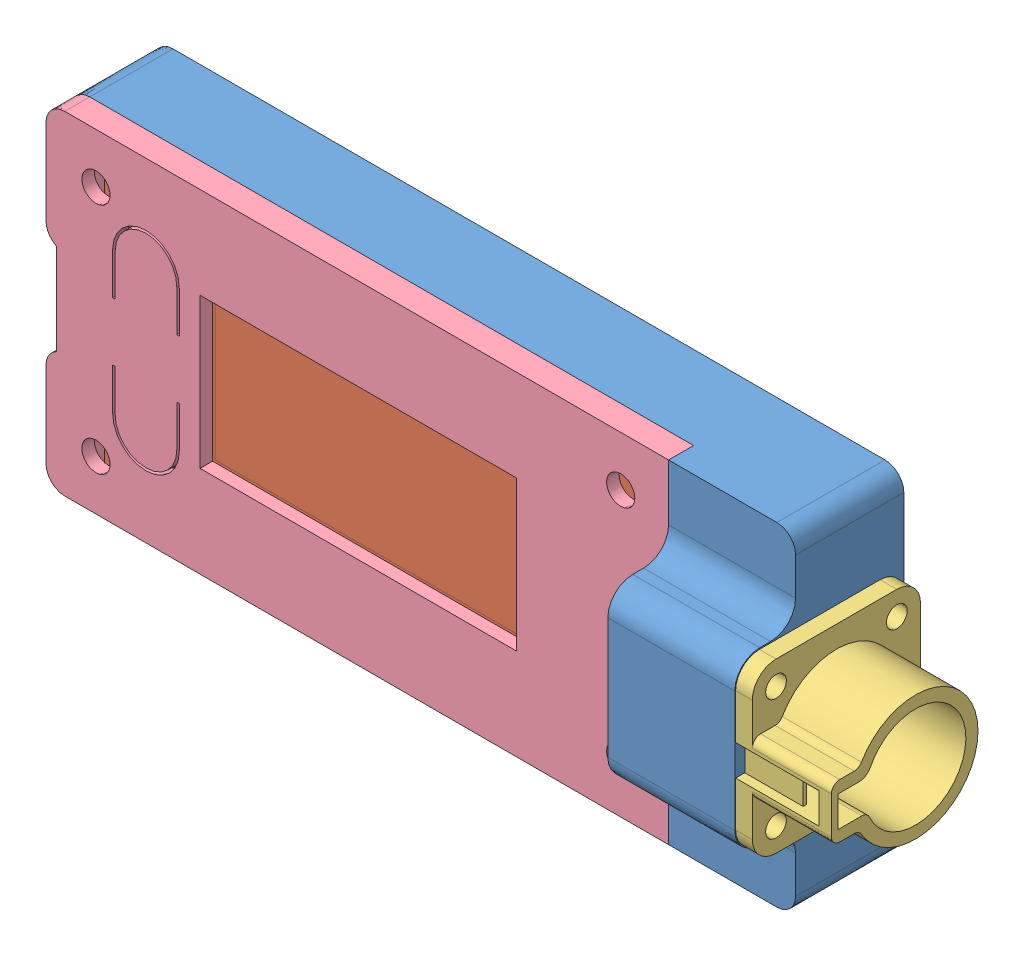
SolidWorks assembly ass-long, configuration Default. Lengths in mm.
Overall size (101.5 40 32.8).
4 component instances, 4 part files, 9 mates.
Components (placement in the parent):
- etna-1: etna [Default] at (-37.6304 -7.9619 -92.9396) size (90 40 20.3)
- pcb01-main-2: pcb01-main [Default] at (-0.1304 12.0381 -83.9396) x (-1 0 0) z (0 0 -1) size (71 35 12)
- RPC1-12RB-6P-1: RPC1-12RB-6P [Default] at (54.3696 12.0381 -82.8396) x (0 -1 0) z (-1 0 0) size (20.2 20.2 22.2)
- etna-top-1: etna-top [Default] at (-37.6304 -7.9619 -82.9396) size (74.75 40 3.7)
Mates (geometry in assembly coordinates):
- Coincident1: coincident anti-aligned: plane of etna-1 through (-37.6304 -7.9619 -83.9396) normal (0 0 1); plane of pcb01-main-2 through (34.8696 -5.4619 -83.9396) normal (0 0 -1)
- Concentric1: concentric aligned: circle of etna-1; circle of pcb01-main-2
- Concentric2: concentric aligned: circle of etna-1; circle of pcb01-main-2
- Width1: width anti-aligned: plane of RPC1-12RB-6P-1 through (54.3696 22.1381 -90.0896) normal (0 1 0); plane of RPC1-12RB-6P-1 through (54.3696 1.9381 -75.5896) normal (0 -1 0); plane of etna-1 through (-37.6304 -7.9619 -82.9396) normal (0 -1 0); plane of etna-1 through (-37.6304 32.0381 -82.9396) normal (0 1 0)
- Coincident5: coincident aligned: plane of etna-1 through (-37.6304 -7.9619 -92.9396) normal (0 0 -1); plane of RPC1-12RB-6P-1 through (54.3696 4.7881 -92.9396) normal (0 0 -1)
- Coincident7: coincident anti-aligned: plane of etna-1 through (52.3696 -7.9619 -82.9396) normal (1 0 0); plane of RPC1-12RB-6P-1 through (52.3696 12.0381 -82.8396) normal (-1 0 0)
- Coincident8: coincident aligned: plane of etna-1 through (-37.6304 -7.9619 -82.9396) normal (0 -1 0); plane of etna-top-1 through (-37.6304 -7.9619 -79.9396) normal (0 -1 0)
- Coincident9: coincident anti-aligned: plane of etna-1 through (-37.6304 -7.9619 -82.9396) normal (0 0 1); plane of etna-top-1 through (-37.6304 -7.9619 -82.9396) normal (0 0 -1)
- Coincident11: coincident anti-aligned: plane of etna-1 through (37.1196 -5.7119 -171.8731) normal (-1 0 0); plane of etna-top-1 through (37.1196 -7.9619 -79.9396) normal (1 0 0)
